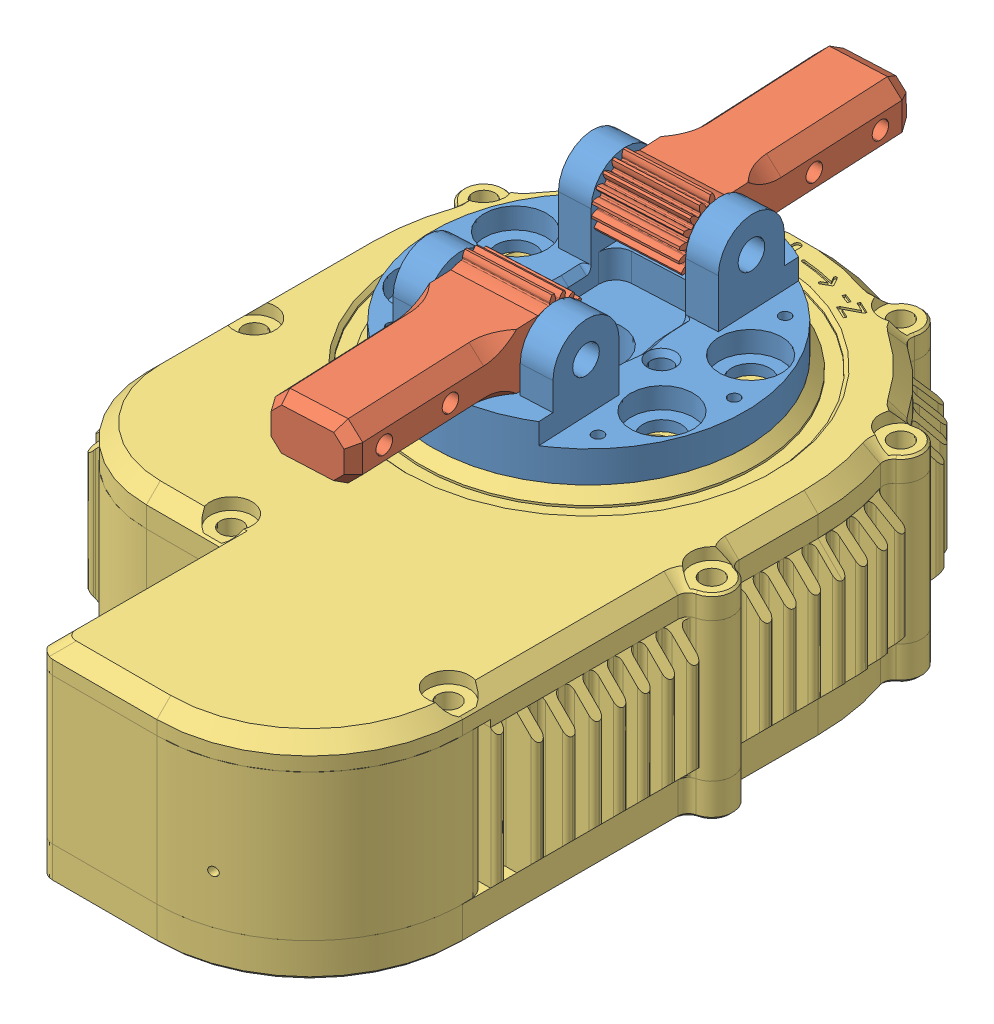
SolidWorks assembly HEBI Robotics-A-2055-01, configuration Default. Lengths in mm.
Overall size (73.14 48.13 115.89).
4 component instances, 3 part files, 6 mates.
Components (placement in the parent):
- HEBI Robotics-A-2055-01_PM-2218-01-1: HEBI Robotics-A-2055-01_PM-2218-01 [Default] at (0 11.4247 0) x (-0.047086 0 -0.998891) z (0.998891 0 -0.047086) size (45 32.5 45)
- HEBI Robotics-A-2055-01_PM-2221-01-1: HEBI Robotics-A-2055-01_PM-2221-01 [Default] at (-0.5886 22.9247 -12.4861) x (-0.047085 0.002855 -0.998887) z (0.998891 0 -0.047086) size (35.49 9.86 12)
- HEBI Robotics-A-2055-01_PM-2221-01-2: HEBI Robotics-A-2055-01_PM-2221-01 [Default] at (0.5886 22.9247 12.4861) x (0.047085 0.002855 0.998887) z (-0.998891 0 0.047086) size (35.49 9.86 12)
- HEBI Robotics-A-2055-01_X5-Export-1: HEBI Robotics-A-2055-01_X5-Export [Default] at (0 -4.6253 0) x (0 0 1) z (0 1 0) size (109.71 73.14 31.05)
Mates (geometry in assembly coordinates):
- Coincident1: coincident anti-aligned: plane of HEBI Robotics-A-2055-01_PM-2218-01-1 through (0 11.4247 0) normal (0 -1 0); plane of HEBI Robotics-A-2055-01_X5-Export-1 through (0 11.4247 0) normal (0 1 0)
- Concentric1: concentric anti-aligned: cylinder of HEBI Robotics-A-2055-01_PM-2218-01-1 through (0 17.9247 0) axis (0 -1 0) radius 22.5; circle of HEBI Robotics-A-2055-01_X5-Export-1
- Width1: width anti-aligned: plane of HEBI Robotics-A-2055-01_PM-2221-01-2 through (6.5819 22.9247 12.2036) normal (0.998891 0 -0.047086); plane of HEBI Robotics-A-2055-01_PM-2218-01-1 through (-5.4048 22.9247 12.7686) normal (-0.998891 0 0.047086); plane of HEBI Robotics-A-2055-01_PM-2221-01-2 through (-10.3992 22.9247 13.0041) normal (-0.998891 0 0.047086); plane of HEBI Robotics-A-2055-01_PM-2218-01-1 through (11.5764 22.9247 11.9682) normal (0.998891 0 -0.047086)
- Concentric3: concentric anti-aligned: cylinder of HEBI Robotics-A-2055-01_PM-2221-01-2 through (6.5819 22.9247 12.2036) axis (0.998891 0 -0.047086) radius 2.775; cylinder of HEBI Robotics-A-2055-01_PM-2218-01-1 through (11.5764 22.9247 11.9682) axis (-0.998891 0 0.047086) radius 5
- Width2: width aligned: plane of HEBI Robotics-A-2055-01_PM-2221-01-1 through (23.7001 22.9247 -13.6311) normal (0.998891 0 -0.047086); plane of HEBI Robotics-A-2055-01_PM-2218-01-1 through (11.7134 22.9247 -13.066) normal (-0.998891 0 0.047086); plane of HEBI Robotics-A-2055-01_PM-2221-01-1 through (10.3992 22.9247 -13.0041) normal (0.998891 0 -0.047086); plane of HEBI Robotics-A-2055-01_PM-2218-01-1 through (-11.5764 22.9247 -11.9682) normal (-0.998891 0 0.047086)
- Concentric4: concentric aligned: cylinder of HEBI Robotics-A-2055-01_PM-2218-01-1 through (10.3992 22.9247 -13.0041) axis (-0.998891 0 0.047086) radius 5; cylinder of HEBI Robotics-A-2055-01_PM-2221-01-1 through (11.7134 22.9247 -13.066) axis (-0.998891 0 0.047086) radius 2.775
